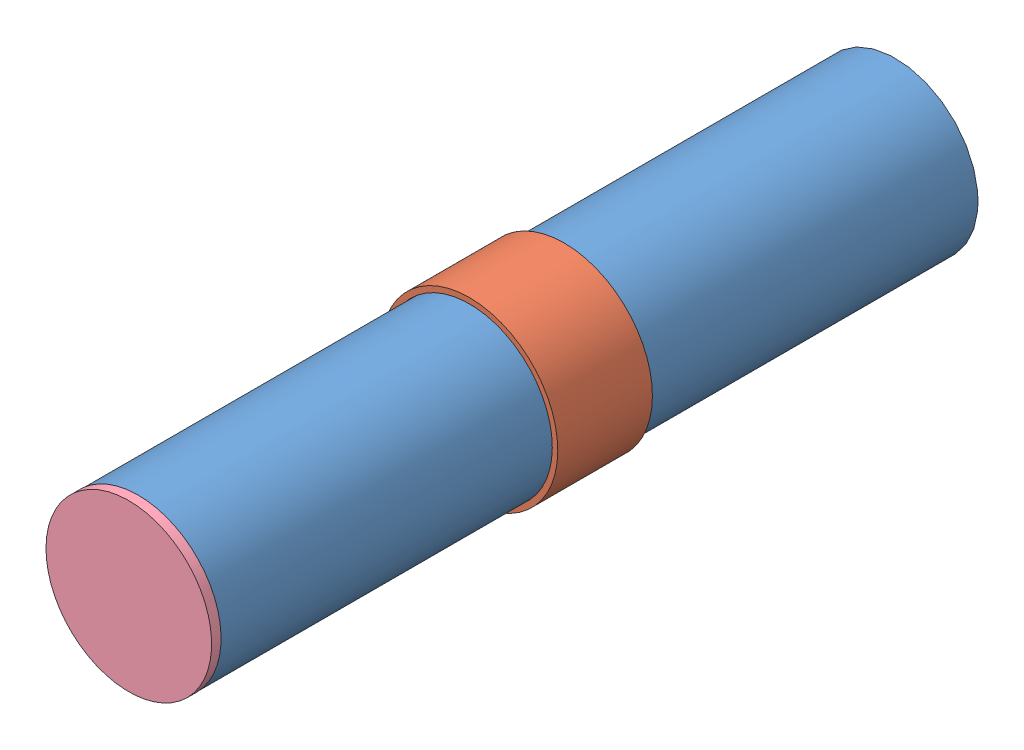
SolidWorks assembly CouplerAssem, configuration Default. Lengths in mm.
Overall size (60.16 60.16 205.74).
4 component instances, 4 part files, 6 mates.
Components (placement in the parent):
- 1.75inchCoupler-1: 1.75inchCoupler [Default] at (64.3262 103.4466 62.2164) size (44.37 44.37 203.2)
- Coupler1.75inchBodyTube-1: Coupler1.75inchBodyTube [Default] at (64.3262 103.4466 151.1164) x (0.99999 -0.004378 0) z (0 0 1) size (47.4 47.4 25.4)
- SmallCouplerBulkPlate1.75-1: SmallCouplerBulkPlate1.75 [Default] at (64.3262 103.4466 262.8764) x (0.947457 -0.319882 0) z (0 0 1) size (41.27 41.27 2.54)
- LargeCouplerBulkPlate1.75-1: LargeCouplerBulkPlate1.75 [Default] at (64.3262 103.4466 265.4164) x (0.471656 -0.881783 0) z (0 0 1) size (44.45 44.45 2.54)
Mates (geometry in assembly coordinates):
- Concentric1: concentric aligned: circle of 1.75inchCoupler-1; circle of Coupler1.75inchBodyTube-1
- Distance1: distance = 88.9 mm aligned: plane of 1.75inchCoupler-1 through (64.3262 103.4466 265.4164) normal (0 0 1); plane of Coupler1.75inchBodyTube-1 through (64.3262 103.4466 176.5164) normal (0 0 1)
- Concentric2: concentric aligned: cylinder of SmallCouplerBulkPlate1.75-1 through (64.3262 103.4466 265.4164) axis (0 0 -1) radius 20.6375; cylinder of LargeCouplerBulkPlate1.75-1 through (64.3262 103.4466 267.9564) axis (0 0 -1) radius 22.225
- Concentric3: concentric aligned: cylinder of 1.75inchCoupler-1 through (64.3262 103.4466 265.4164) axis (0 0 -1) radius 20.6375; cylinder of SmallCouplerBulkPlate1.75-1 through (64.3262 103.4466 265.4164) axis (0 0 -1) radius 20.6375
- Coincident1: coincident aligned: circle of 1.75inchCoupler-1; circle of SmallCouplerBulkPlate1.75-1
- Distance2: distance = 0 mm anti-aligned: plane of SmallCouplerBulkPlate1.75-1 through (64.3262 103.4466 265.4164) normal (0 0 1); plane of LargeCouplerBulkPlate1.75-1 through (64.3262 103.4466 265.4164) normal (0 0 -1)
